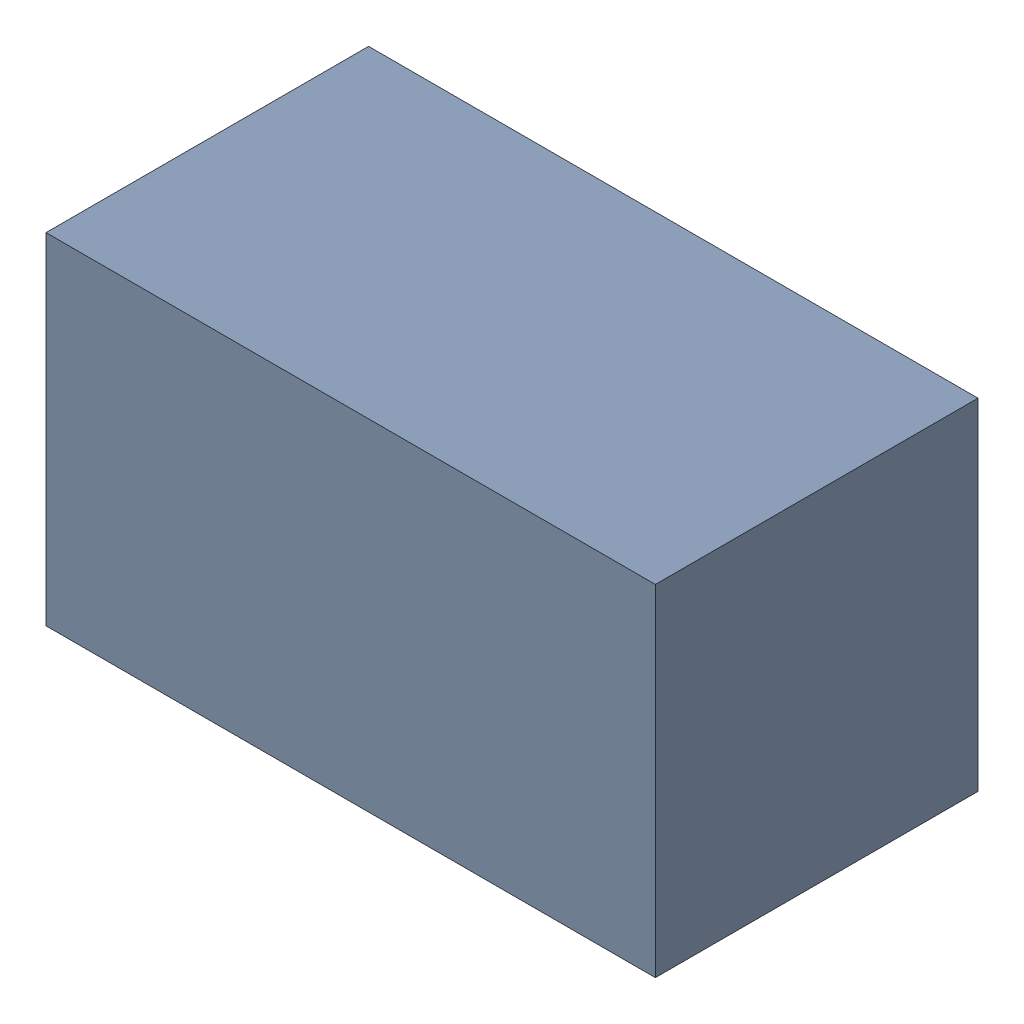
SolidWorks assembly R3, configuration Default. Lengths in mm.
Overall size (1.7 0.95 0.9).
2 component instances, 1 part files, 0 mates.
Components (placement in the parent):
- 580483600-1: 580483600 [Default] at (215.138 109.474 0) size (1.7 0.95 0.9)
  - Extruded_3-1: Extruded_3 [Default] at origin size (1.7 0.95 0.9)
